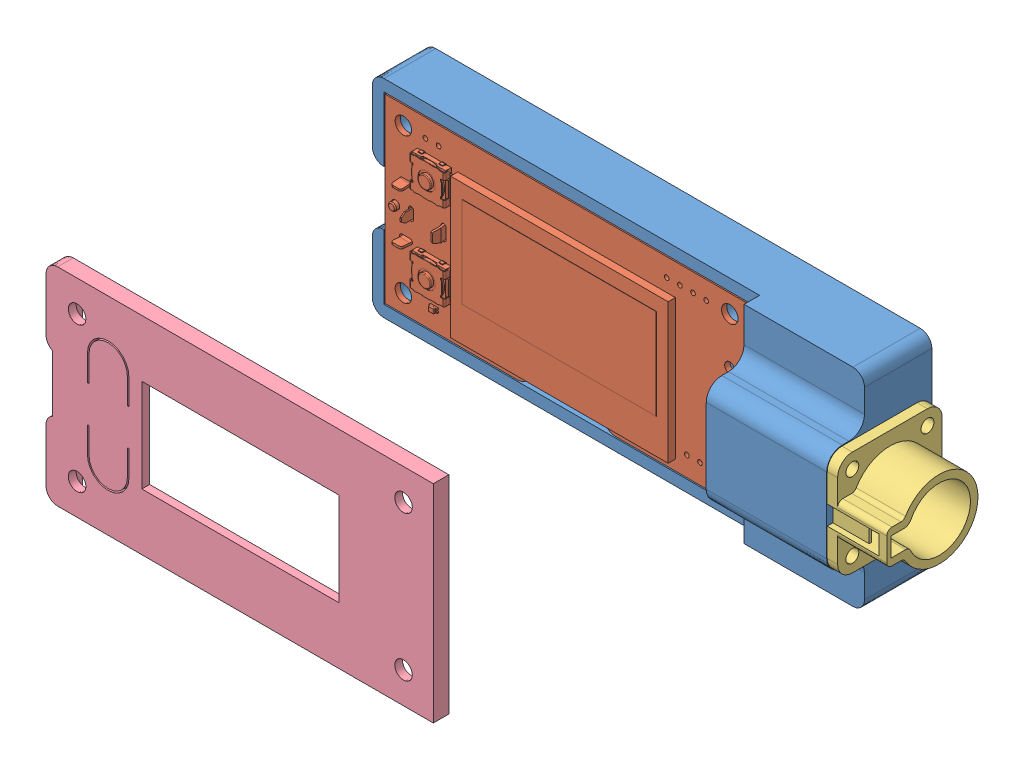
SolidWorks assembly Assem2, configuration Default. Lengths in mm.
Overall size (109.5 40 72.97).
4 component instances, 4 part files, 8 mates.
Components (placement in the parent):
- etna-new-1: etna-new [Default] at (-37.6304 -7.9619 -92.9396) size (98 40 20.3)
- pcb01-main-2: pcb01-main [Default] at (-0.1304 12.0381 -83.9396) x (-1 0 0) z (0 0 -1) size (71 35 12)
- RPC1-12RB-6P-1: RPC1-12RB-6P [Default] at (62.3696 12.0381 -82.8396) x (0 -1 0) z (-1 0 0) size (20.2 20.2 22.2)
- etna-top-1: etna-top [Default] at (-37.6304 -7.9619 -22.968) size (74.75 40 3.7)
Mates (geometry in assembly coordinates):
- Coincident1: coincident anti-aligned: plane of etna-new-1 through (-37.6304 -7.9619 -83.9396) normal (0 0 1); plane of pcb01-main-2 through (34.8696 -5.4619 -83.9396) normal (0 0 -1)
- Concentric1: concentric aligned: circle of etna-new-1; circle of pcb01-main-2
- Concentric2: concentric aligned: circle of etna-new-1; circle of pcb01-main-2
- Width1: width anti-aligned: plane of RPC1-12RB-6P-1 through (62.3696 22.1381 -90.0896) normal (0 1 0); plane of RPC1-12RB-6P-1 through (62.3696 1.9381 -75.5896) normal (0 -1 0); plane of etna-new-1 through (-37.6304 -7.9619 -82.9396) normal (0 -1 0); plane of etna-new-1 through (-37.6304 32.0381 -82.9396) normal (0 1 0)
- Coincident5: coincident aligned: plane of etna-new-1 through (-37.6304 -7.9619 -92.9396) normal (0 0 -1); plane of RPC1-12RB-6P-1 through (62.3696 4.7881 -92.9396) normal (0 0 -1)
- Coincident7: coincident anti-aligned: plane of etna-new-1 through (60.3696 -7.9619 -82.9396) normal (1 0 0); plane of RPC1-12RB-6P-1 through (60.3696 12.0381 -82.8396) normal (-1 0 0)
- Coincident8: coincident aligned: plane of etna-new-1 through (-37.6304 -7.9619 -82.9396) normal (0 -1 0); plane of etna-top-1 through (-37.6304 -7.9619 -19.968) normal (0 -1 0)
- Coincident11: coincident anti-aligned: plane of etna-new-1 through (37.1196 -5.7119 -171.8731) normal (-1 0 0); plane of etna-top-1 through (37.1196 -7.9619 -19.968) normal (1 0 0)
